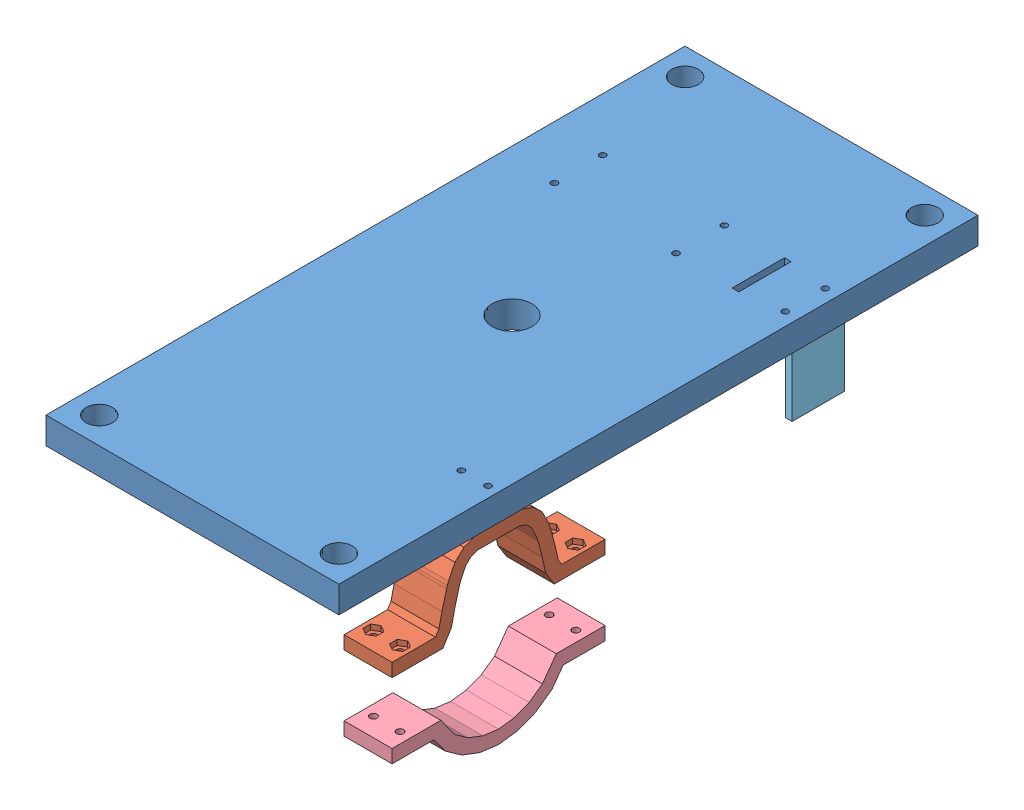
SolidWorks assembly z-stage_assembly, configuration Default. Lengths in mm.
Overall size (139.7 104.32 304.8).
7 component instances, 6 part files, 15 mates.
Components (placement in the parent):
- z-stage-1: z-stage [Default] at (-58.0965 -17.6851 71.3487) size (139.7 12.7 304.8)
- clamp_top-1: clamp_top [Default] at (81.6035 -49.246 0.7136) x (0 -1 -0.000104) z (-1 0 0) size (38.6 101.6 22.86)
- 3Mx0.5in_screw-1: 3Mx0.5in_screw [Default] at (76.5235 -21.5798 -4.8513) x (1 0 0) z (0 0 -1) size (6 15.7 6)
- 3Mx0.5in_screw-2: 3Mx0.5in_screw [Default] at (63.8235 -21.5798 -4.8513) x (1 0 0) z (0 0 -1) size (6 15.7 6)
- ChargerPlugOfftheShelf-1: ChargerPlugOfftheShelf [Default] at (102.9395 -72.6724 -4.807) x (0 0 1) z (-1 0 0) (suppressed, hidden)
- clamp_bottom-1: clamp_bottom [Default] at (58.7435 -50.1713 -10.3228) x (0 -1 -0.000104) z (1 0 0) size (23.77 101.6 22.86)
- camera_mount-1: camera_mount [Default] at (72.4235 -17.6851 -169.7513) x (1 0 0) z (0 0 -1) size (9.18 28.17 25)
Mates (geometry in assembly coordinates):
- Concentric1: concentric: cylinder of clamp_top-1 through (76.5235 -23.9798 -4.8513) axis (0 -1 0) radius 1.7; cylinder of 3Mx0.5in_screw-1 through (76.5235 -8.8798 -4.8513) axis (0 -1 0) radius 1.5
- Concentric2: concentric: cylinder of clamp_top-1 through (63.8235 -23.9798 -4.8513) axis (0 -1 0) radius 1.7; cylinder of 3Mx0.5in_screw-2 through (63.8235 -8.8798 -4.8513) axis (0 -1 0) radius 1.5
- Coincident1: coincident: plane of z-stage-1 through (-58.0965 -17.6851 71.3487) normal (0 -1 0); plane of clamp_top-1 through (58.7435 -17.6851 6.4359) normal (0 1 0)
- Coincident2: coincident: plane of clamp_top-1 through (74.8235 -21.5798 -4.8513) normal (0 -1 0); circle of 3Mx0.5in_screw-1
- Coincident3: coincident: plane of clamp_top-1 through (62.1235 -21.5798 -4.8513) normal (0 -1 0); plane of 3Mx0.5in_screw-2 through (63.8235 -21.5798 -4.8513) normal (0 1 0)
- Distance1: distance = 21.336 mm: plane of clamp_top-1 through (81.6035 -49.246 0.7136) normal (1 0 0); plane of ChargerPlugOfftheShelf-1 through (102.9395 -65.2369 21.3269) normal (1 0 0)
- Coincident9: coincident: plane of clamp_top-1 through (81.6035 -49.246 0.7136) normal (1 0 0); plane of clamp_bottom-1 through (81.6035 -50.1713 -10.3228) normal (1 0 0)
- Coincident8: coincident: plane of clamp_top-1 through (58.7435 -56.2872 45.9947) normal (0 -0.000104 1); plane of clamp_bottom-1 through (81.6035 -85.5366 45.9917) normal (0 -0.000104 1)
- Width1: width: plane of clamp_top-1 through (58.7435 -56.2872 45.9947) normal (0 -0.000104 1); plane of clamp_top-1 through (58.7435 -56.2766 -55.6053) normal (0 0.000104 -1); cylinder of ChargerPlugOfftheShelf-1 through (173.9395 -72.6724 -4.807) axis (-1 0 0) radius 21.983
- Parallel3: parallel: plane of z-stage-1 through (-58.0965 -4.9851 71.3487) normal (0 1 0); plane of ChargerPlugOfftheShelf-1 through (108.5828 -31.3436 -4.807) normal (0 1 0)
- Coincident10: coincident: circle of z-stage-1; cylinder of 3Mx0.5in_screw-1 through (76.5235 -8.8798 -4.8513) axis (0 -1 0) radius 1.5
- Concentric9: concentric: circle of z-stage-1; circle of 3Mx0.5in_screw-2
- Concentric10: concentric: circle of z-stage-1; circle of camera_mount-1
- Coincident12: coincident: plane of z-stage-1 through (-58.0965 -17.6851 71.3487) normal (0 -1 0); plane of camera_mount-1 through (72.4235 -17.6851 -169.7513) normal (0 1 0)
- Concentric11: concentric: circle of z-stage-1; circle of camera_mount-1
